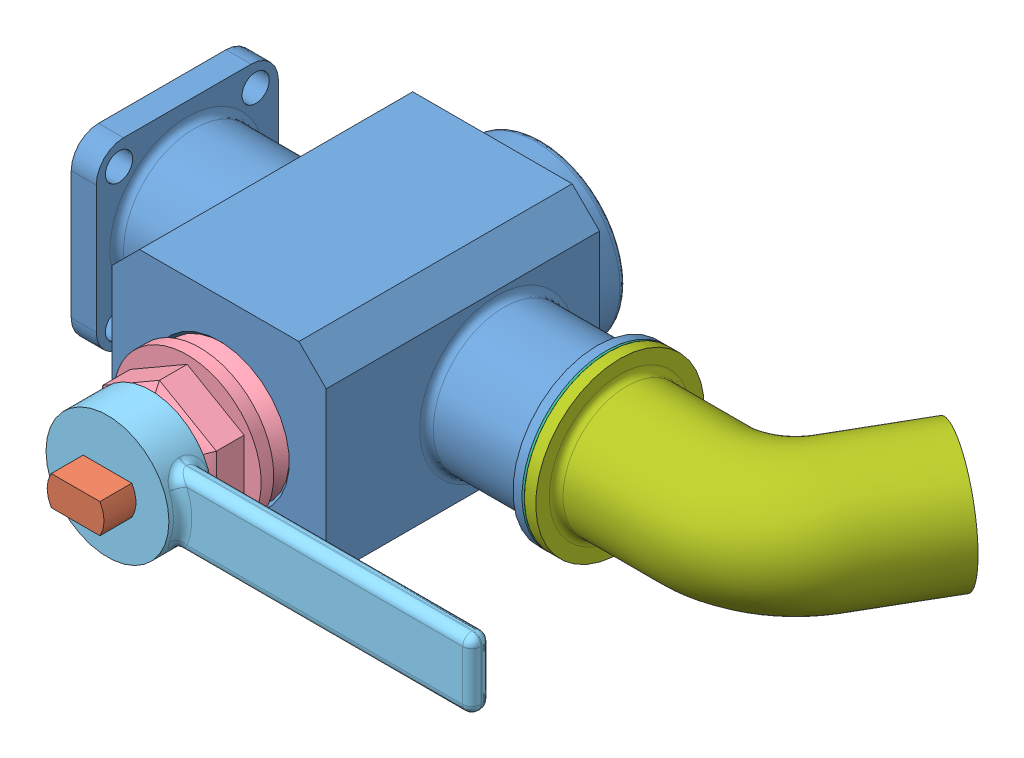
SolidWorks assembly Сборка крана, configuration По умолчанию. Lengths in mm.
Overall size (317.32 104.14 207.14).
7 component instances, 7 part files, 15 mates.
Components (placement in the parent):
- Корпус-2: Корпус [По умолчанию] at (158.2406 172.0438 17.5368) x (-1 0 0) z (0 -1 0) size (195 142 96)
- Пробка-2: Пробка [По умолчанию] at (158.2406 172.0438 106.609) x (0 0 -1) z (1 0 0) size (180 58 58)
- Втулка-2: Втулка [По умолчанию] at (158.2406 172.0438 111.609) x (0 0 1) z (-1 0 0) size (15 57 57)
- Крышка-3: Крышка [По умолчанию] at (158.2406 172.0438 141.109) x (0 0 -1) z (1 0 0) size (46.01 65 65)
- Рукоятка-1: Рукоятка [По умолчанию] at (158.2406 172.0438 167.609) size (181 54 19.07)
- Уплотнительная прокладка-1: Уплотнительная прокладка [По умолчанию] at (253.2406 172.0438 62.5368) x (0 0.773302 -0.634037) z (1 0 0) size (74 74 1)
- Колено-1: Колено [По умолчанию] at (259.2406 172.0438 62.5368) x (1 0 0) z (0 -1 0) size (151.32 106.07 74)
Mates (geometry in assembly coordinates):
- Концентричный1: concentric aligned: circle of Корпус-2; circle of Пробка-2
- Совпадение1: coincident aligned: cone of Корпус-2 through (158.2406 172.0438 102.5368) axis (0 0 -1); cone of Пробка-2 through (158.2406 172.0438 20.609) axis (0 0 -1)
- Концентричный5: concentric anti-aligned: circle of Корпус-2; circle of Втулка-2
- Совпадение4: coincident anti-aligned: plane of Пробка-2 through (158.2406 184.5438 106.609) normal (0 0 1); plane of Втулка-2 through (158.2406 145.5438 106.609) normal (0 0 -1)
- Концентричный6: concentric aligned: circle of Корпус-2; circle of Крышка-3
- Совпадение6: coincident anti-aligned: plane of Втулка-2 through (158.2406 152.0438 121.609) normal (0 0 1); plane of Крышка-3 through (158.2406 151.5438 121.609) normal (0 0 -1)
- Совпадение10: coincident anti-aligned: plane of Крышка-3 through (158.2406 172.0438 167.609) normal (0 0 1); plane of Рукоятка-1 through (158.2406 172.0438 167.609) normal (0 0 -1)
- Концентричный7: concentric anti-aligned: cylinder of Пробка-2 through (158.2406 172.0438 106.609) axis (0 0 1) radius 12.5; cylinder of Рукоятка-1 through (158.2406 172.0438 186.609) axis (0 0 -1) radius 12.5
- Совпадение11: coincident anti-aligned: circle of Корпус-2; circle of Уплотнительная прокладка-1
- Концентричный8: concentric aligned: circle of Корпус-2; circle of Уплотнительная прокладка-1
- Концентричный9: concentric anti-aligned: circle of Уплотнительная прокладка-1; circle of Колено-1
- Совпадение12: coincident anti-aligned: plane of Уплотнительная прокладка-1 through (254.2406 172.0438 62.5368) normal (1 0 0); plane of Колено-1 through (254.2406 172.0438 62.5368) normal (-1 0 0)
- Совпадение13: coincident anti-aligned: plane of Пробка-2 through (129.2406 165.5438 172.609) normal (0 -1 0); plane of Рукоятка-1 through (147.5635 165.5438 186.609) normal (0 1 0)
- Параллельность4: parallel anti-aligned: line of Корпус-2 through (193.2406 220.0438 137.5368) axis (-1 0 0); line of Пробка-2 through (147.5635 178.5438 200.609) axis (1 0 0)
- Совпадение14: coincident anti-aligned: plane of Корпус-2 through (253.2406 172.0438 41.0368) normal (1 0 0); plane of Уплотнительная прокладка-1 through (253.2406 172.0438 62.5368) normal (-1 0 0)
